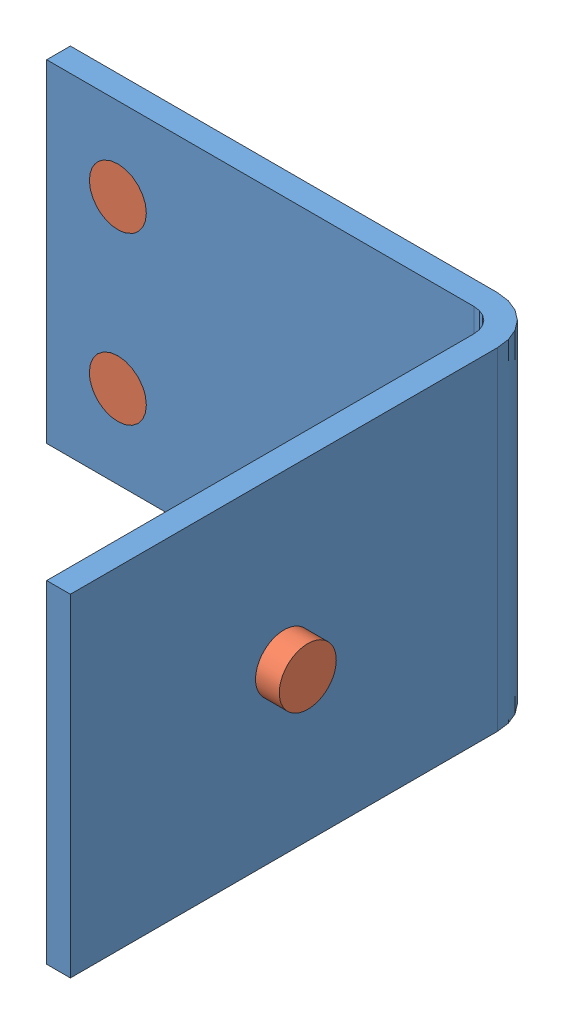
SolidWorks assembly busbar_assembly, configuration Default. Lengths in mm.
Overall size (105 70 105).
4 component instances, 2 part files, 8 mates.
Components (placement in the parent):
- busbar-1: busbar [Default] at origin size (100 70 100)
- bolt-1: bolt [Default] at origin size (12 12 10)
- bolt-2: bolt [Default] at (0 -35 0) size (12 12 10)
- bolt-3: bolt [Default] at (95 -17.5 35) x (0 0 1) z (-1 0 0) size (12 12 10)
Mates (geometry in assembly coordinates):
- InPlace1: in place: plane of ? through (0 50 0) normal (0 0 1); plane of ? through (0 0 0) normal (0 0 1); moOrthogonalPlaneRef_w of ? through (0 50 0) normal (0 0 1); plane of ? through (0 0 0) normal (0 1 0); plane of ? through (0 50 0) normal (0 0 1); plane of ? through (0 0 0) normal (1 0 0); plane of ? through (0 70 0) normal (0 0 1); unknown of ?
- Coincident1: coincident aligned: plane of busbar-1; plane of bolt-1
- Coincident2: coincident aligned: moOrthogonalPlaneRef_w of busbar-1 through (0 0 0) normal (0 1 0); plane of bolt-1 through (0 0 0) normal (0 1 0)
- Coincident3: coincident anti-aligned: moOrthogonalPlaneRef_w of busbar-1 through (0 0 0) normal (-1 0 0); plane of bolt-1 through (0 0 0) normal (1 0 0)
- Coincident4: coincident aligned: plane of busbar-1 through (0 70 0) normal (0 0 1); plane of bolt-2 through (15 17.5 0) normal (0 0 1)
- Coincident5: coincident aligned: circle of busbar-1; circle of bolt-2
- Coincident6: coincident aligned: plane of bolt-3 through (95 35 50) normal (-1 0 0); plane of busbar-1 through (95 70 5) normal (-1 0 0)
- Coincident7: coincident aligned: circle of busbar-1; circle of bolt-3
